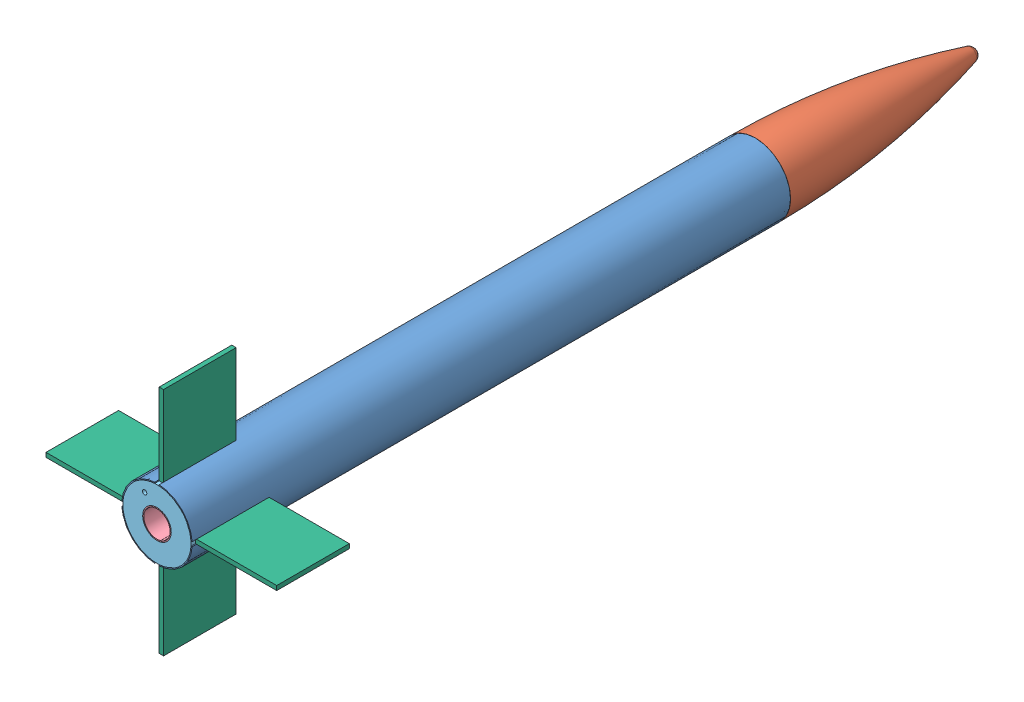
SolidWorks assembly L1 Cert Rocket, configuration Default. Lengths in mm.
Overall size (333.01 333.01 1181.1).
10 component instances, 6 part files, 25 mates.
Components (placement in the parent):
- Body Tube-1: Body Tube [Default] at origin size (101.6 101.6 863.6)
- Nose Cone-1: Nose Cone [Default] at (0 0 114.3) x (0.711538 -0.702648 0) z (0.702648 0.711538 0) size (101.6 431.8 101.6)
- Solid Centering Ring-1: Solid Centering Ring [Default] at (0 0 752.475) x (0.423606 0.905847 0) z (0 0 -1) size (98.42 98.42 6.35)
- MMT-1: MMT [Default] at (0 0 863.6) x (0.5 -0.866025 0) z (0 0 -1) size (41.27 41.27 279.4)
- Centering Ring with Hardware Hole-1: Centering Ring with Hardware Hole [Default] at (0 0 590.55) x (0.5 -0.866025 0) z (0 0 -1) size (98.42 98.42 6.35)
- Centering Ring with Hardware Hole-2: Centering Ring with Hardware Hole [Default] at (0 0 863.6) x (0.5 -0.866025 0) z (0 0 -1) size (98.42 98.42 6.35)
- Fin-1: Fin [Default] at (3.175 96.3296 809.473) x (0 1 0) z (-1 0 0) size (146.05 104.78 6.35)
- Fin-2: Fin [Default] at (-3.175 -96.3296 809.473) x (0 -1 0) z (1 0 0) size (146.05 104.78 6.35)
- Fin-3: Fin [Default] at (96.3296 -3.175 809.473) x (1 0 0) z (0 1 0) size (146.05 104.78 6.35)
- Fin-4: Fin [Default] at (-96.3296 3.175 809.473) x (-1 0 0) z (0 -1 0) size (146.05 104.78 6.35)
Mates (geometry in assembly coordinates):
- Coincident1: coincident anti-aligned: plane of Body Tube-1 through (0 0 0) normal (0 0 -1); plane of Nose Cone-1 through (34.497 -34.0659 0) normal (0 0 1)
- Concentric1: concentric anti-aligned: circle of Body Tube-1; circle of Nose Cone-1
- Concentric2: concentric aligned: cylinder of MMT-1 through (0 0 584.2) axis (0 0 1) radius 20.6375; cylinder of Centering Ring with Hardware Hole-1 through (0 0 584.2) axis (0 0 1) radius 20.6375
- Coincident2: coincident aligned: plane of MMT-1 through (0 0 584.2) normal (0 0 -1); plane of Centering Ring with Hardware Hole-1 through (0 0 584.2) normal (0 0 -1)
- Parallel1: parallel aligned: plane of MMT-1 through (0 0 863.6) normal (-0.866025 -0.5 0); plane of Centering Ring with Hardware Hole-1 through (0 0 590.55) normal (-0.866025 -0.5 0)
- Concentric3: concentric aligned: cylinder of Solid Centering Ring-1 through (0 0 746.125) axis (0 0 1) radius 20.6375; cylinder of MMT-1 through (0 0 584.2) axis (0 0 1) radius 20.6375
- Concentric4: concentric aligned: cylinder of MMT-1 through (0 0 584.2) axis (0 0 1) radius 20.6375; cylinder of Centering Ring with Hardware Hole-2 through (0 0 857.25) axis (0 0 1) radius 20.6375
- Coincident6: coincident aligned: plane of MMT-1 through (0 0 863.6) normal (0 0 1); plane of Centering Ring with Hardware Hole-2 through (0 0 863.6) normal (0 0 1)
- Concentric5: concentric aligned: circle of Centering Ring with Hardware Hole-1; circle of Centering Ring with Hardware Hole-2
- Distance1: distance = 104.775 mm anti-aligned: plane of Solid Centering Ring-1 through (0 0 752.475) normal (0 0 1); plane of Centering Ring with Hardware Hole-2 through (0 0 857.25) normal (0 0 -1)
- Concentric8: concentric anti-aligned: cylinder of MMT-1 through (0 0 584.2) axis (0 0 1) radius 20.6375; cylinder of Fin-2 through (0 0 857.25) axis (0 0 -1) radius 20.701
- Coincident8: coincident anti-aligned: plane of Solid Centering Ring-1 through (0 0 752.475) normal (0 0 1); plane of Fin-2 through (3.175 -20.4561 752.475) normal (0 0 -1)
- Concentric9: concentric anti-aligned: cylinder of MMT-1 through (0 0 584.2) axis (0 0 1) radius 20.6375; cylinder of Fin-3 through (0 0 857.25) axis (0 0 -1) radius 20.701
- Angle1: planar angle = 1.570796 rad anti-aligned: plane of Fin-3 through (96.3296 -3.175 809.473) normal (0 -1 0); plane of Fin-2 through (3.175 -96.3296 809.473) normal (1 0 0)
- Concentric10: concentric anti-aligned: cylinder of MMT-1 through (0 0 584.2) axis (0 0 1) radius 20.6375; cylinder of Fin-1 through (0 0 857.25) axis (0 0 -1) radius 20.701
- Coincident10: coincident aligned: plane of Fin-1 through (-3.175 96.3296 809.473) normal (-1 0 0); plane of Fin-2 through (-3.175 -96.3296 809.473) normal (-1 0 0)
- Coincident11: coincident anti-aligned: plane of Centering Ring with Hardware Hole-2 through (0 0 857.25) normal (0 0 -1); plane of Fin-1 through (-3.175 20.4561 857.25) normal (0 0 1)
- Concentric11: concentric anti-aligned: cylinder of MMT-1 through (0 0 584.2) axis (0 0 1) radius 20.6375; cylinder of Fin-4 through (0 0 857.25) axis (0 0 -1) radius 20.701
- Angle2: planar angle = 4.712389 rad anti-aligned: plane of Fin-4 through (-96.3296 -3.175 809.473) normal (0 -1 0); plane of Fin-2 through (-3.175 -96.3296 809.473) normal (-1 0 0)
- Coincident13: coincident anti-aligned: plane of Solid Centering Ring-1 through (0 0 752.475) normal (0 0 1); plane of Fin-4 through (-20.4561 -3.175 752.475) normal (0 0 -1)
- Concentric12: concentric anti-aligned: cylinder of Body Tube-1 through (0 0 863.6) axis (0 0 -1) radius 49.2125; cylinder of Centering Ring with Hardware Hole-2 through (0 0 857.25) axis (0 0 1) radius 49.2125
- Coincident14: coincident anti-aligned: plane of Centering Ring with Hardware Hole-2 through (0 0 857.25) normal (0 0 -1); plane of Fin-3 through (20.4561 3.175 857.25) normal (0 0 1)
- Angle3: planar angle = 0.523599 rad aligned: plane of MMT-1 through (0 0 863.6) normal (-0.866025 -0.5 0); plane of Fin-1 through (3.175 96.3296 809.473) normal (-1 0 0)
- Coincident17: coincident anti-aligned: plane of Body Tube-1 through (-50.8 -3.175 863.6) normal (0 1 0); plane of Fin-3 through (96.3296 -3.175 809.473) normal (0 -1 0)
- Coincident18: coincident anti-aligned: plane of Body Tube-1 through (-50.8 3.175 752.475) normal (0 0 1); plane of Fin-3 through (20.4561 3.175 752.475) normal (0 0 -1)
